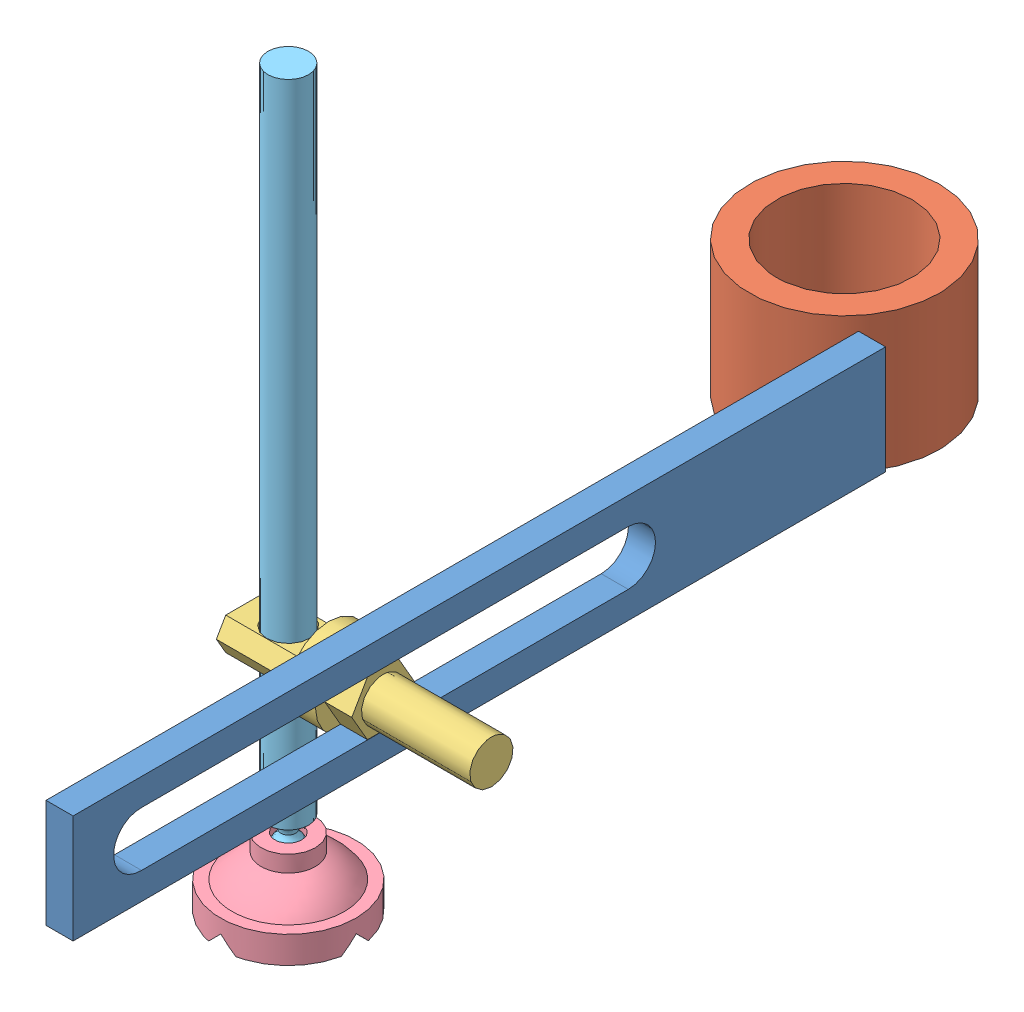
SolidWorks assembly Рычаг, configuration По умолчанию. Lengths in mm.
Overall size (112.22 270.98 357).
5 component instances, 5 part files, 10 mates.
Components (placement in the parent):
- Рейка-1: Рейка [По умолчанию] at (37.2213 5 22) x (0 0 1) z (0 -1 0) size (300 10 40)
- Бобышка-1: Бобышка [По умолчанию] at origin size (70 50 70)
- Ось-1: Ось [По умолчанию] at (27.2213 25.0481 207.5513) x (1 0 0) z (0 -1 -0.000021) size (90 30 30)
- ПризмаDUO-1: ПризмаDUO [По умолчанию] at (2.2213 -59.9258 207.5494) x (-0.004115 0.000021 -0.999992) z (0.999992 0 -0.004115) size (50 25 50)
- Винт15-1: Винт15 [По умолчанию] at (2.2213 -28.9502 207.5501) x (0.99996 0 -0.008949) z (0.008949 -0.000021 0.99996) size (15 255.45 15)
Mates (geometry in assembly coordinates):
- Расстояние6: distance = 22 mm anti-aligned: plane of Рейка-1 through (27.2213 5 22) normal (0 0 -1); plane of assembly through (0 0 0) normal (0 0 1)
- Совпадение6: coincident: line of Рейка-1 through (27.2213 45 22) axis (0 -1 0); cylinder of Бобышка-1 through (0 50 0) axis (0 -1 0) radius 35
- Расстояние1: distance = 5 mm aligned: plane of Бобышка-1 through (0 50 0) normal (0 1 0); plane of Рейка-1 through (27.2213 45 22) normal (0 1 0)
- Совпадение7: coincident anti-aligned: plane of Рейка-1 through (37.2223 35.05 117) normal (0 -1 -0.000021); plane of Ось-1 through (37.2213 35.0482 201.778) normal (0 1 0.000021)
- Расстояние4: distance = 100 mm: point of Ось-1; moEndPointRef_w of Рейка-1
- Совпадение9: coincident aligned: plane of Рейка-1 through (37.2213 5 22) normal (1 0 0); plane of Ось-1 through (37.2213 25.0481 207.5513) normal (1 0 0)
- Концентричный2: concentric anti-aligned: cylinder of Ось-1 through (2.2213 10.0471 207.5509) axis (0 1 0.000021) radius 8; cylinder of Винт15-1 through (2.2213 211.0498 207.5553) axis (0 -1 -0.000021) radius 7.5
- Расстояние5: distance = 180 mm aligned: plane of Винт15-1 through (2.2213 211.0498 207.5553) normal (0 1 0.000021); plane of Ось-1 through (-12.7787 31.0496 215.6333) normal (0 1 0.000021)
- Концентричный3: concentric anti-aligned: cylinder of ПризмаDUO-1 through (2.2213 -29.8577 207.5501) axis (0 1 0.000021) radius 5; cylinder of Винт15-1 through (2.2213 211.0498 207.5553) axis (0 -1 -0.000021) radius 7.5
- Касательность2: tangent: circle of ПризмаDUO-1; torus of Винт15-1
